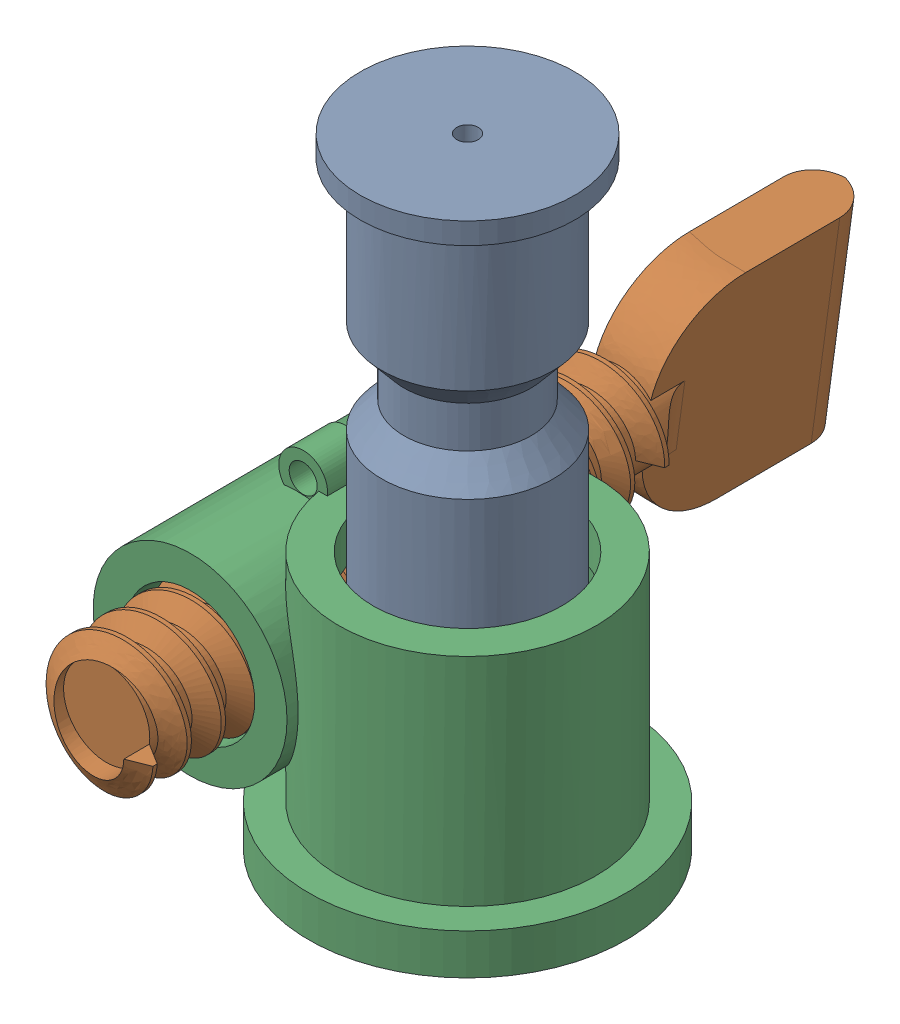
SolidWorks assembly WormGearAssembly, configuration Default. Lengths in mm.
Overall size (9.46 14.45 17.61).
3 component instances, 3 part files, 2 mates.
Components (placement in the parent):
- WormGearVertical-1: WormGearVertical [Default] at (636.6167 851.8751 1290.006) size (5 14.45 5)
- WormGearHorizontal-1: WormGearHorizontal [Default] at (633.1092 851.4294 1282.9808) x (0.990903 -0.134473 -0.005285) z (0.005334 0 0.999986) size (2.87 5.17 17.59)
- wormConnect-1: wormConnect [Default] at (636.6167 848.9294 1290.006) x (0.999986 0 -0.005334) z (0.005334 0 0.999986) size (9.42 6.65 7.4)
Mates (geometry in assembly coordinates):
- Concentric1: concentric aligned: cylinder of WormGearVertical-1 through (636.6167 861.8751 1290.006) axis (0 -1 0) radius 2; cylinder of wormConnect-1 through (636.6167 847.9294 1290.006) axis (0 -1 0) radius 2.5
- Concentric2: concentric anti-aligned: cylinder of WormGearHorizontal-1 through (633.1732 851.4294 1294.9806) axis (-0.005334 0 -0.999986) radius 1; cylinder of wormConnect-1 through (633.1307 851.4294 1287.0246) axis (0.005334 0 0.999986) radius 1.5
